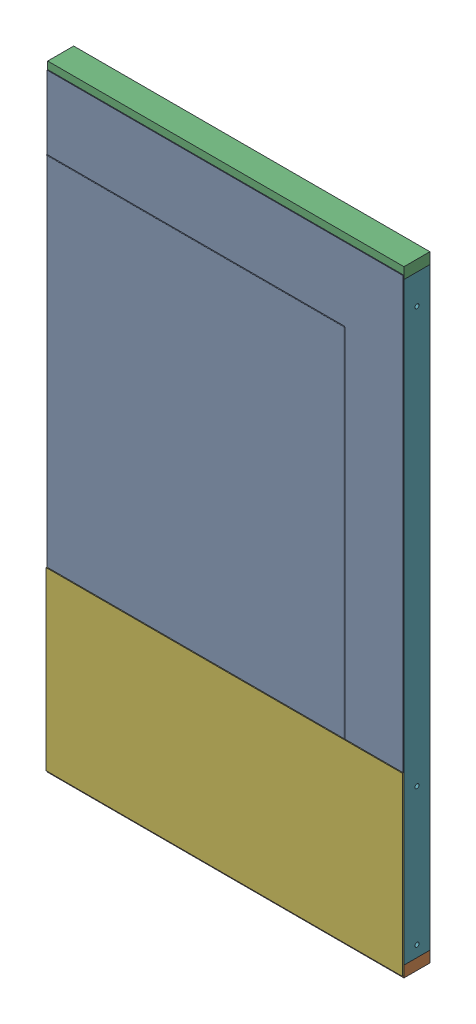
SolidWorks assembly door panel, configuration Default. Lengths in mm.
Overall size (1219.2 2108.2 94.46).
9 component instances, 6 part files, 23 mates.
Components (placement in the parent):
- LZipperDoor-2: LZipperDoor [Default] at (-609.6 1327.15 44.45) size (1219.2 1473.2 3.81)
- basic panel-1: basic panel [Default] at origin size (1219.2 2108.2 94.46)
  - 2x4x48-1: 2x4x48 [Default] x (0 0 -1) z (0 1 0) size (88.9 1219.2 38.1)
  - 2x4x48-2: 2x4x48 [Default] at (0 2070.1 0) x (0 0 1) z (0 -1 0) size (88.9 1219.2 38.1)
  - 2x4x21-1: 2x4x21 [Default] at (-609.6 552.45 0) x (0 0 -1) z (-1 0 0) size (88.9 533.4 38.1)
  - 2x4x45-1: 2x4x45 [Default] at (-38.1 571.5 0) x (0 0 1) z (0 -1 0) size (88.9 1143 38.1)
  - plywoodx48x23.7 plywood-1: plywoodx48x23.7 plywood [Default] at (-609.6 289.56 44.45) x (1 0 0) z (0 -1 0) size (1219.2 5.56 601.98)
  - 2x4x80-Hole-1: 2x4x80-Hole [Default] at (-19.05 19.05 0) x (0 0 -1) z (1 0 0) size (88.9 2032 38.1)
  - 2x4x80-Hole-2: 2x4x80-Hole [Default] at (-1200.15 19.05 0) x (0 0 1) z (-1 0 0) size (88.9 2032 38.1)
Mates (geometry in assembly coordinates):
- Coincident30: coincident anti-aligned: plane of 2x4x41.75-2 through (-1130.3 2028.825 0) normal (-1 0 0); plane of 2x4x57.25-1 through (-1130.3 2047.875 44.45) normal (1 0 0)
- Coincident31: coincident aligned: plane of 2x4x41.75-2 through (-1130.3 2047.875 -44.45) normal (0 0 -1); plane of 2x4x57.25-1 through (-1130.3 2047.875 -44.45) normal (0 0 -1)
- Coincident32: coincident aligned: plane of 2x4x41.75-2 through (-1130.3 2047.875 44.45) normal (0 1 0); plane of 2x4x57.25-1 through (-1149.35 2047.875 0) normal (0 1 0)
- Coincident33: coincident anti-aligned: plane of 2x4x41.75-1 through (-1130.3 612.775 0) normal (-1 0 0); plane of 2x4x57.25-1 through (-1130.3 2047.875 44.45) normal (1 0 0)
- Coincident34: coincident aligned: plane of 2x4x41.75-1 through (-1130.3 631.825 -44.45) normal (0 0 -1); plane of 2x4x57.25-1 through (-1130.3 2047.875 -44.45) normal (0 0 -1)
- Coincident35: coincident aligned: plane of 2x4x41.75-1 through (-1130.3 593.725 44.45) normal (0 -1 0); plane of 2x4x57.25-1 through (-1149.35 593.725 0) normal (0 -1 0)
- Coincident36: coincident anti-aligned: plane of 2x4x41.75-1 through (-79.375 612.775 0) normal (1 0 0); plane of 2x4x57.25-2 through (-79.375 593.725 44.45) normal (-1 0 0)
- Coincident37: coincident aligned: plane of 2x4x41.75-1 through (-1130.3 593.725 44.45) normal (0 -1 0); plane of 2x4x57.25-2 through (-60.325 593.725 0) normal (0 -1 0)
- Coincident38: coincident aligned: plane of 2x4x41.75-1 through (-1130.3 631.825 -44.45) normal (0 0 -1); plane of 2x4x57.25-2 through (-79.375 593.725 -44.45) normal (0 0 -1)
- Coincident42: coincident anti-aligned: plane of 2x4x41.375-2 through (-1130.3 2009.775 44.45) normal (0 -1 0); plane of 1488A11_Surface-Mount Hinge with Holes-2 through (-39.6875 2009.775 46.355) normal (0 1 0)
- Coincident43: coincident aligned: plane of 1488A11_Surface-Mount Hinge with Holes-1 through (-6.35 708.025 46.355) normal (1 0 0); plane of 1488A11_Surface-Mount Hinge with Holes-2 through (-6.35 2009.775 46.355) normal (1 0 0)
- Coincident44: coincident anti-aligned: plane of 2x4x41.375-1 through (-1130.3 631.825 44.45) normal (0 1 0); plane of 1488A11_Surface-Mount Hinge with Holes-1 through (-73.025 631.825 46.355) normal (0 -1 0)
- Coincident45: coincident anti-aligned: plane of 2x4x57.25-1 through (-1130.3 2047.875 44.45) normal (0 0 1); plane of plywoodx44.375x57.25-1 through (-604.8375 1320.8 44.45) normal (0 0 -1)
- Coincident46: coincident aligned: plane of 2x4x57.25-1 through (-1168.4 2047.875 44.45) normal (-1 0 0); plane of plywoodx44.375x57.25-1 through (-1168.4 593.725 50.0063) normal (-1 0 0)
- Coincident47: coincident aligned: plane of 2x4x41.375-2 through (-1130.3 2047.875 44.45) normal (0 1 0); plane of plywoodx44.375x57.25-1 through (-1168.4 2047.875 50.0063) normal (0 1 0)
- Coincident52: coincident anti-aligned: plane of plywoodx44.375x57.25-1 through (-604.8375 1320.8 44.45) normal (0 0 -1); plane of 2x4x41.375-3 through (-1130.3 1349.375 44.45) normal (0 0 1)
- Coincident53: coincident anti-aligned: plane of 2x4x57.25-1 through (-1130.3 2047.875 44.45) normal (1 0 0); plane of 2x4x41.375-3 through (-1130.3 1330.325 0) normal (-1 0 0)
- Distance6: distance = 679.45 mm anti-aligned: plane of 2x4x41.375-1 through (-1130.3 631.825 44.45) normal (0 1 0); plane of 2x4x41.375-3 through (-1130.3 1311.275 44.45) normal (0 -1 0)
- Coincident65: coincident aligned: line of 1889A54_Draw Latch-1 through (-1211.411 1349.375 -44.45) axis (1 0 0); line of 2x4x41.375-3 through (-1130.3 1349.375 -44.45) axis (1 0 0)
- Distance8: distance = 3.81 mm: line of Half Inch Weather Stripping-1 through (-1181.1 2051.05 -44.45) axis (0 -1 0); plane of 1889A54_Draw Latch-1 through (-1184.91 1337.7494 -46.0502) normal (1 0 0)
- Coincident66: coincident anti-aligned: plane of LZipperDoor-2 through (-609.6 1327.15 44.45) normal (0 0 -1); plane of basic panel-1/2x4x80-Hole-2 through (-1219.2 2051.05 44.45) normal (0 0 1)
- Coincident67: coincident aligned: plane of LZipperDoor-2 through (-1219.2 2063.75 46.99) normal (-1 0 0); plane of basic panel-1/2x4x80-Hole-2 through (-1219.2 2051.05 -44.45) normal (-1 0 0)
- Coincident68: coincident anti-aligned: plane of LZipperDoor-2 through (-1219.2 590.55 46.99) normal (0 -1 0); plane of basic panel-1/2x4x45-1 through (-1181.1 590.55 -44.45) normal (0 1 0)
